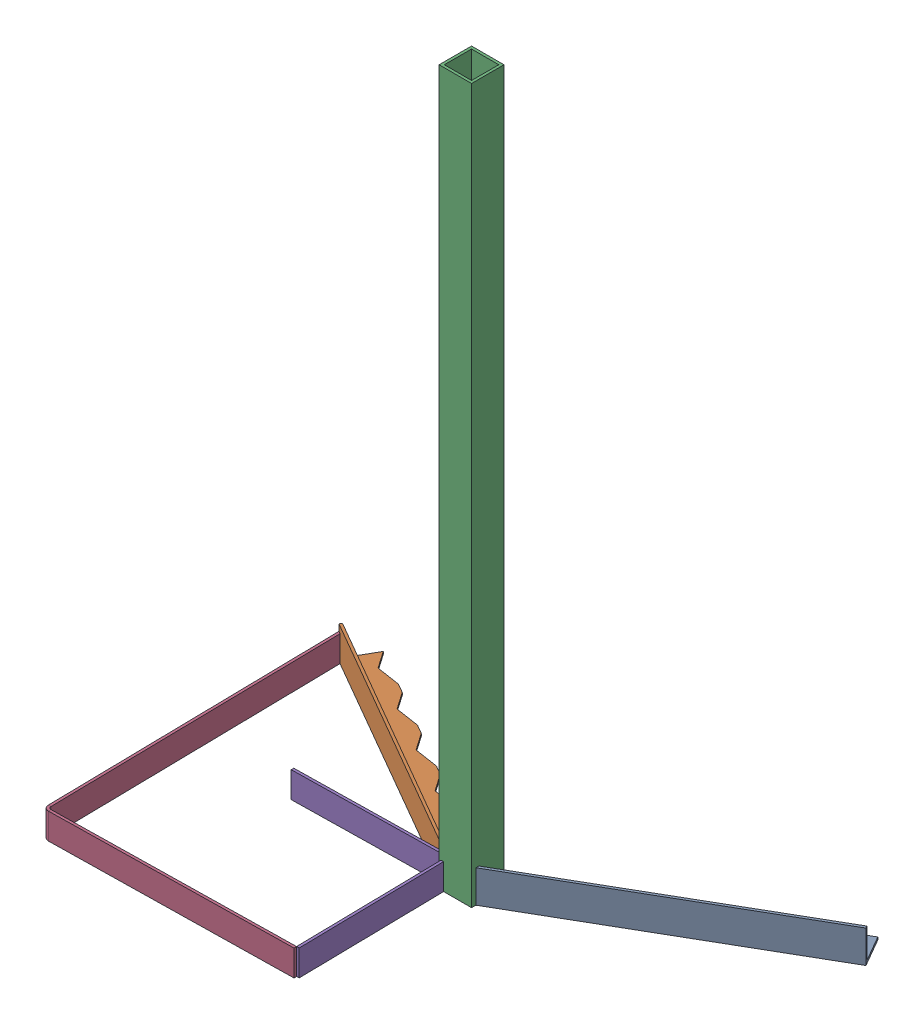
SolidWorks assembly LSTСБ, configuration По умолчанию. Lengths in mm.
Overall size (406.05 550 253.62).
5 component instances, 4 part files, 14 mates.
Components (placement in the parent):
- Борт25-1: Борт25 [По умолчанию] at (12.5 0 21.6506) x (0.866025 0 -0.5) z (0.5 0 0.866025) size (220 25 25)
- Борт25-2: Борт25 [По умолчанию] at (-203.0256 0 -88.3494) x (0.866025 0 0.5) z (-0.5 0 0.866025) size (220 25 25)
- Основание25-1: Основание25 [По умолчанию] at (0 0 12.5) size (25 550 25)
- ГИБ2-1: ГИБ2 [По умолчанию] at (-9.0056 0 140.2993) x (-0.999848 0 0.017452) z (-0.017452 0 -0.999848) size (190 20 232)
- ГИБ1-1: ГИБ1 [По умолчанию] at (-129.1168 0 20.3773) x (0.999848 0 -0.017452) z (0.017452 0 0.999848) size (120 20 120)
Mates (geometry in assembly coordinates):
- Совпадение2: coincident: point of Борт25-1
- Совпадение3: coincident anti-aligned: line of Борт25-1 through (190.5256 0 -110) axis (-0.866025 0 0.5)
- Совпадение4: coincident: point of Борт25-1; point of Борт25-2
- Совпадение5: coincident anti-aligned: line of Борт25-2 through (0 0 0) axis (-0.866025 0 -0.5)
- Совпадение6: coincident anti-aligned: plane of Борт25-1 through (203.0256 0 -88.3494) normal (0 -1 0)
- Совпадение7: coincident anti-aligned: plane of Борт25-2 through (-12.5 0 21.6506) normal (0 -1 0)
- Совпадение12: coincident anti-aligned: plane of Основание25-1 through (-12.5 550 0) normal (0 0 -1)
- Совпадение14: coordinate: moEndPointRef_w of Основание25-1
- Совпадение15: coincident anti-aligned: plane of ГИБ2-1 through (-9.0405 0 138.2996) normal (0 -1 0)
- Совпадение16: coincident aligned: line of Борт25-2 through (-203.0256 25 -88.3494) axis (0 -1 0); line of ГИБ2-1 through (-203.0256 20 -88.3494) axis (0 -1 0)
- Угол1: planar angle = 5.253441 rad aligned: plane of ГИБ2-1 through (-198.9766 0 143.6153) normal (-0.999848 0 0.017452); plane of Борт25-2 through (-12.5 25 21.6506) normal (-0.5 0 0.866025)
- Совпадение18: coincident aligned: line of ГИБ2-1 through (-9.0405 20 138.2996) axis (0 -1 0); line of ГИБ1-1 through (-9.0405 20 138.2996) axis (0 -1 0)
- Совпадение19: coincident aligned: plane of ГИБ2-1 through (-9.0405 0 138.2996) normal (0 -1 0); plane of ГИБ1-1 through (-9.1002 0 20.2827) normal (0 -1 0)
- Параллельность1: parallel anti-aligned: plane of ГИБ2-1 through (-198.9766 0 143.6153) normal (-0.999848 0 0.017452); plane of ГИБ1-1 through (-9.1351 0 18.283) normal (0.999848 0 -0.017452)
